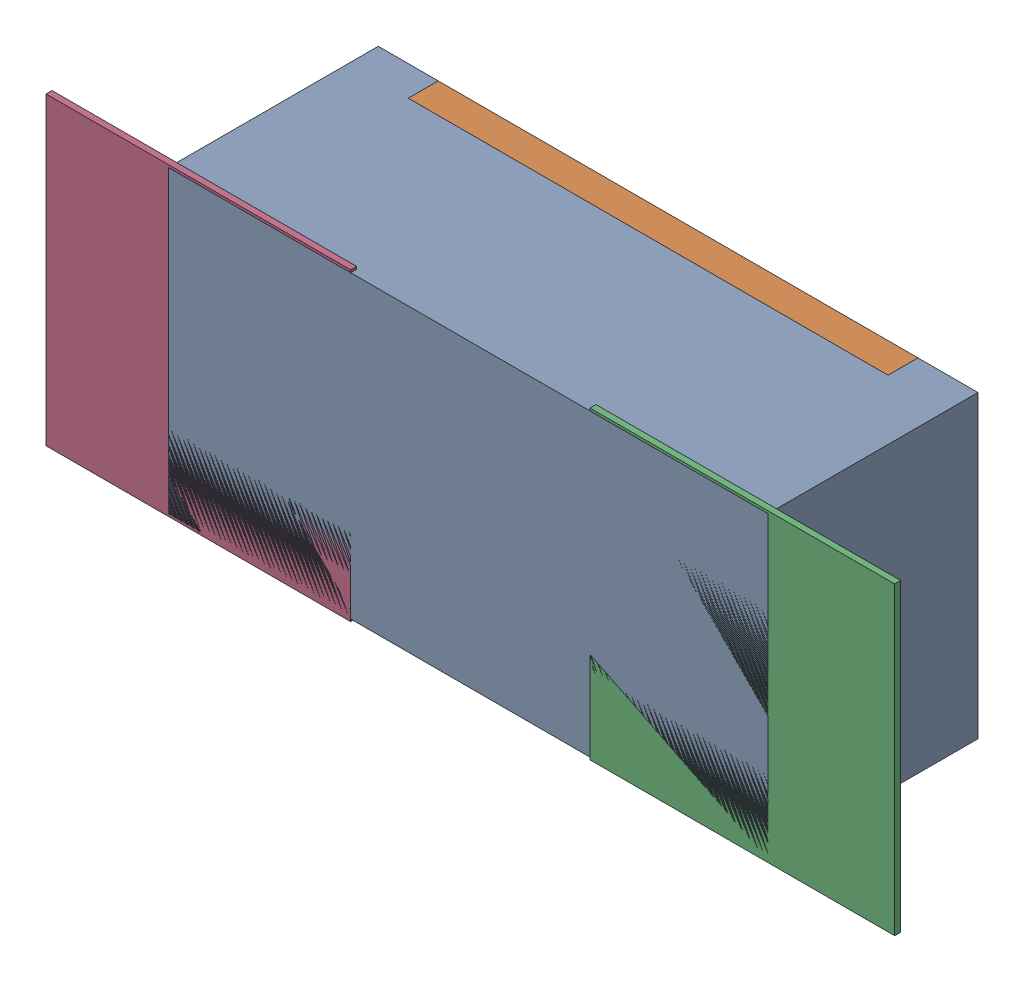
SolidWorks assembly R114, configuration Défaut. Lengths in mm.
Overall size (1.42 0.51 0.35).
5 component instances, 2 part files, 0 mates.
Components (placement in the parent):
- R0402-1: R0402 [Défaut] at (23.2332 -1.4393 -2.0818) x (-1 0 0) z (0 0 -1) size (1 0.5 0.35)
- 6504207776-1: 6504207776 [Défaut] at (23.6902 -1.4392 -2.0918) size (0.51 0.51 0.01)
  - Extruded-1: Extruded [Défaut] at origin size (0.51 0.51 0.01)
- 6504207776-2: 6504207776 [Défaut] at (22.7832 -1.4392 -2.0918) size (0.51 0.51 0.01)
  - Extruded-1: Extruded [Défaut] at origin size (0.51 0.51 0.01)
